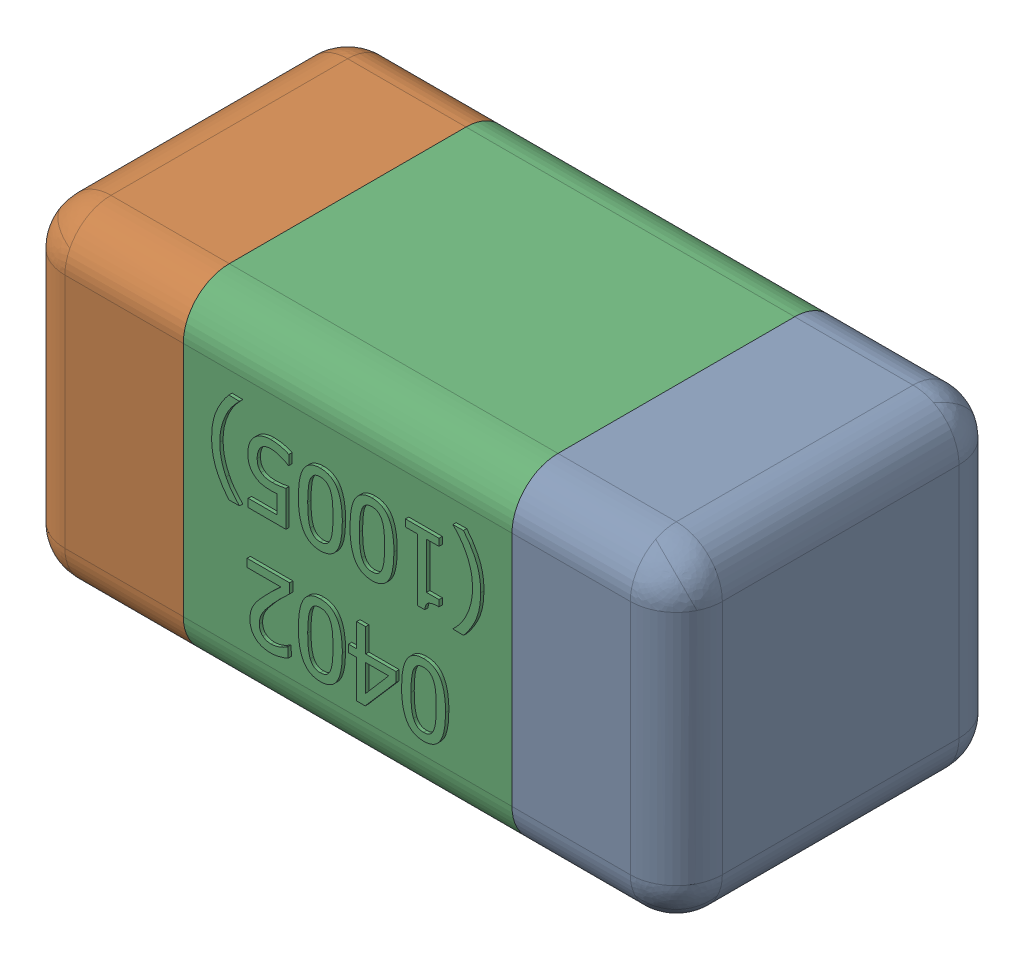
SolidWorks assembly C46, configuration Standard. Lengths in mm.
Overall size (1.01 0.51 0.51).
4 component instances, 3 part files, 0 mates.
Components (placement in the parent):
- C46-subassembly-1-1: C46-subassembly-1 [Standard] at (3.2999 10.9 0) x (-1 0 0) z (0 0 1) size (1.01 0.51 0.51)
  - User Library-0402_Cap-1: User Library-0402_Cap [Standard] at origin size (0.26 0.51 0.51)
  - User Library-0402_Cap-1-1: User Library-0402_Cap-1 [Standard] at origin size (0.26 0.5 0.51)
  - User Library-0402_Cap-2-1: User Library-0402_Cap-2 [Standard] at origin size (0.5 0.5 0.51)
